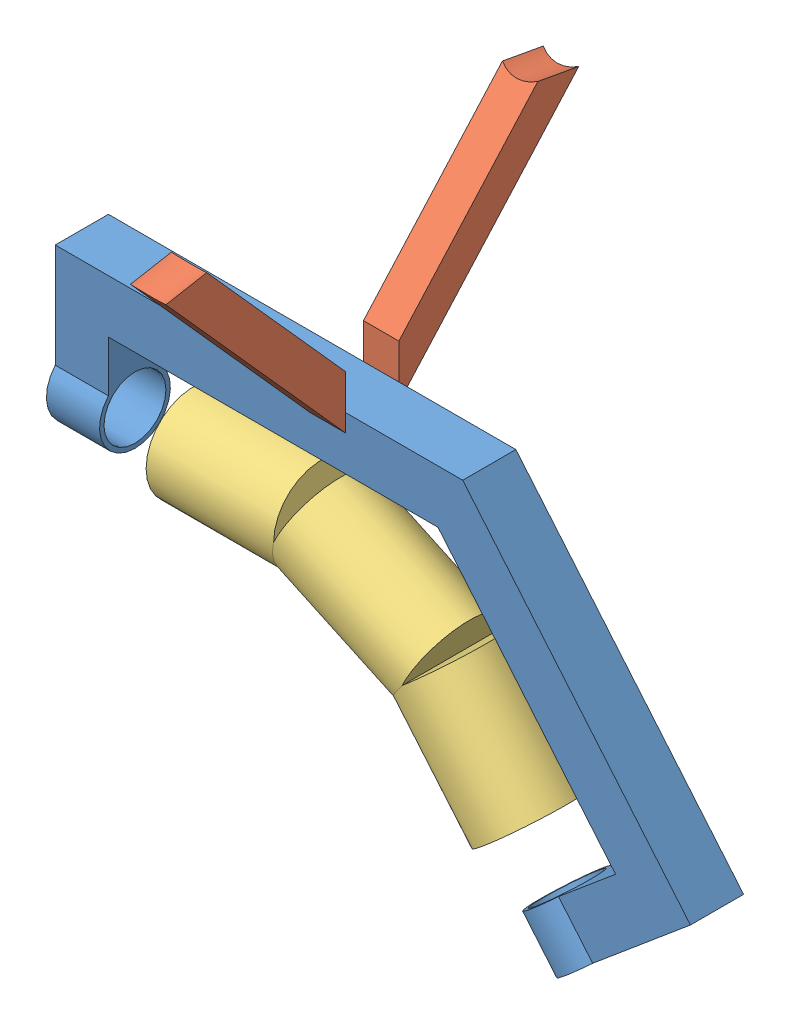
SolidWorks assembly Steering Mount Sub, configuration Default. Lengths in mm.
Overall size (263.28 319.37 167.66).
3 component instances, 3 part files, 8 mates.
Components (placement in the parent):
- Steering Column Mount-1: Steering Column Mount [Default] at (32.8911 -63.5217 17.1259) size (227.72 140.26 25.4)
- column mount y-1: column mount y [Default] at (-28.6826 92.3266 -65.2847) x (0 0 -1) z (1 0 0) size (148 74.75 12.7)
- Double U Joint Mockup-1: Double U Joint Mockup [Default] at (-86.471 14.2103 17.1259) size (150.75 84.35 33.91)
Mates (geometry in assembly coordinates):
- Coincident1: coincident anti-aligned: plane of Steering Column Mount-1 through (32.8911 -63.5217 26.6509) normal (0 0 1); plane of column mount y-1 through (-35.0326 53.5803 26.6509) normal (0 0 -1)
- Coincident2: coincident aligned: line of Steering Column Mount-1 through (-107.4226 53.5803 26.6509) axis (1 0 0); line of column mount y-1 through (-35.0326 53.5803 26.6509) axis (1 0 0)
- Distance1: distance = 91.44 mm aligned: plane of column mount y-1 through (-35.0326 92.3266 -65.2847) normal (-1 0 0); plane of Steering Column Mount-1 through (-126.4726 14.2103 7.6009) normal (-1 0 0)
- Coincident3: coincident anti-aligned: line of Steering Column Mount-1 through (-107.4226 14.2103 17.1259) axis (-1 0 0); line of Double U Joint Mockup-1 through (-86.471 14.2103 17.1259) axis (1 0 0)
- Parallel1: parallel aligned: plane of Steering Column Mount-1 through (-126.4726 14.2103 7.6009) normal (-1 0 0); plane of Double U Joint Mockup-1 through (-86.471 14.2103 17.1259) normal (-1 0 0)
- Parallel2: parallel anti-aligned: plane of Steering Column Mount-1 through (47.5109 -57.5763 7.6009) normal (-0.642788 0.766044 0); plane of Double U Joint Mockup-1 through (34.6777 -42.2822 17.1259) normal (0.642788 -0.766044 0)
- Coincident5: coincident aligned: line of Steering Column Mount-1 through (59.756 -72.1694 17.1259) axis (-0.642788 0.766044 0); line of Double U Joint Mockup-1 through (34.6777 -42.2822 17.1259) axis (-0.642788 0.766044 0)
- Distance2: distance = 12.7 mm: line of column mount y-1 through (-35.0326 53.5803 7.6009) axis (1 0 0); line of Steering Column Mount-1 through (-107.4226 40.8803 7.6009) axis (1 0 0)
